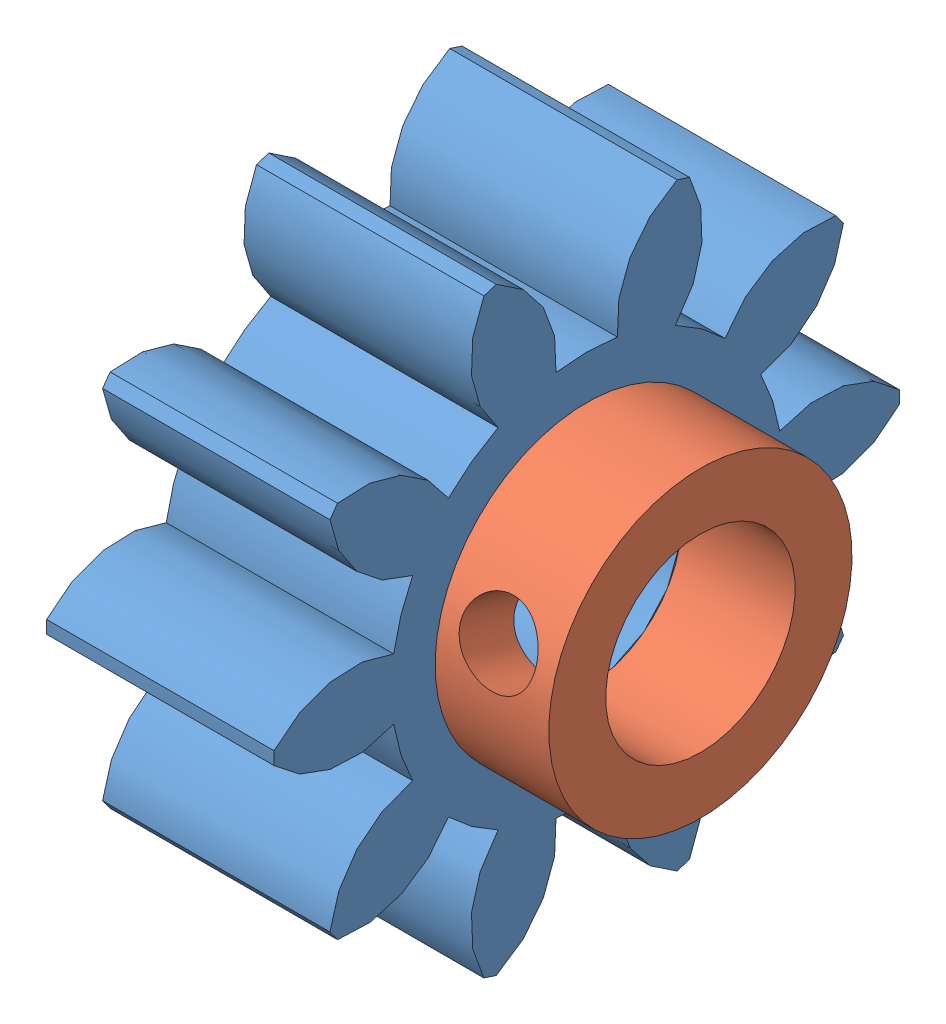
SolidWorks assembly Assem3, configuration Default. Lengths in mm.
Overall size (9 15.79 16.5).
2 component instances, 2 part files, 1 mates.
Components (placement in the parent):
- Metric - Spur gear 1.375M 10T 20PA 6FW ---S10N75H50L5N-1: Metric - Spur gear 1.375M 10T 20PA 6FW ---S10N75H50L5N [Metric - Spur gear 1.375M 10T 20PA 6FW ---S10N75H50L5N] at (-2.9954 0.3214 -0.2208) size (6 15.79 16.5)
- gear_space-1: gear_space [Default] at (3.0046 0.3214 -0.2208) x (0 -0.285059 -0.95851) z (0 -0.95851 0.285059) size (8 3 8)
Mates (geometry in assembly coordinates):
- Coincident1: coincident aligned: circle of Metric - Spur gear 1.375M 10T 20PA 6FW ---S10N75H50L5N-1; circle of gear_space-1
